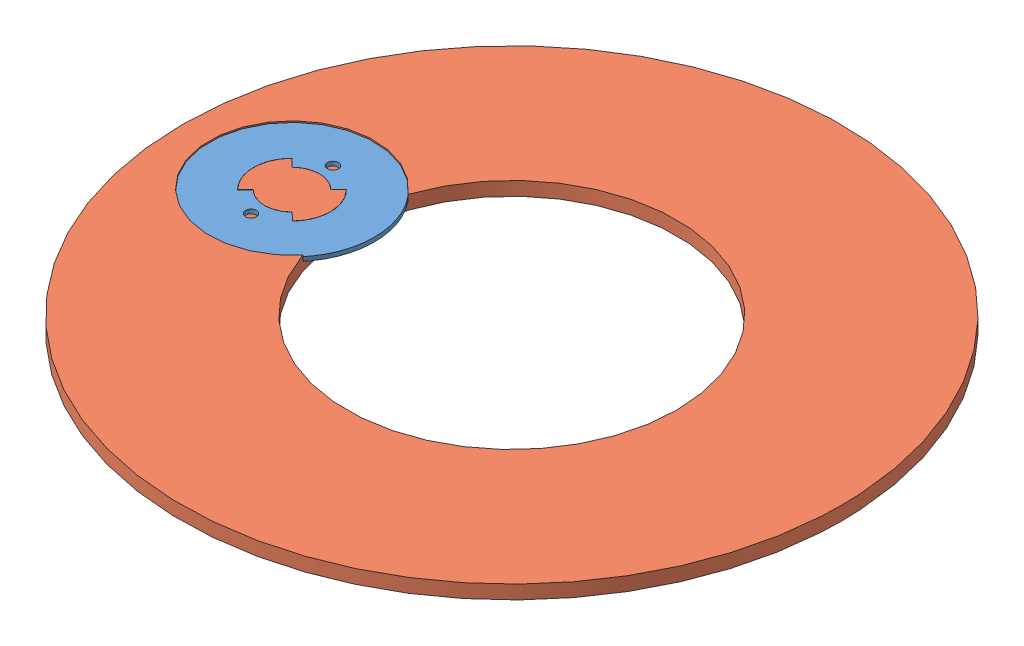
SolidWorks assembly Cell-Prototype-1, configuration Default. Lengths in mm.
Overall size (430 5 430).
2 component instances, 2 part files, 5 mates.
Components (placement in the parent):
- Plate-Modified-1: Plate-Modified [Default] at (-135 4.5 -55) x (-0.005675 0 -0.999984) z (0 -1 0) size (60 60 1.5)
- Main Carousel^Cell-Prototype-1-1: Main Carousel^Cell-Prototype-1 [Default] at (-55 0 -55) x (1 0 0) z (0 1 0) size (240 240 5) (virtual)
Mates (geometry in assembly coordinates):
- Concentric1: concentric: circle of Main Carousel^Cell-Prototype-1-1; circle of assembly
- Coincident2: coincident: circle of Main Carousel^Cell-Prototype-1-1; circle of assembly
- Concentric2: concentric: circle of Main Carousel^Cell-Prototype-1-1; circle of assembly
- Coincident4: coincident: plane of Plate-Modified-1 through (-135 3 -55) normal (0 -1 0); plane of Main Carousel^Cell-Prototype-1-1 through (-135 3 -55) normal (0 1 0)
- Concentric3: concentric: cylinder of Plate-Modified-1 through (-135 3 -55) axis (0 1 0) radius 30; cylinder of Main Carousel^Cell-Prototype-1-1 through (-135 3 -55) axis (0 1 0) radius 30
